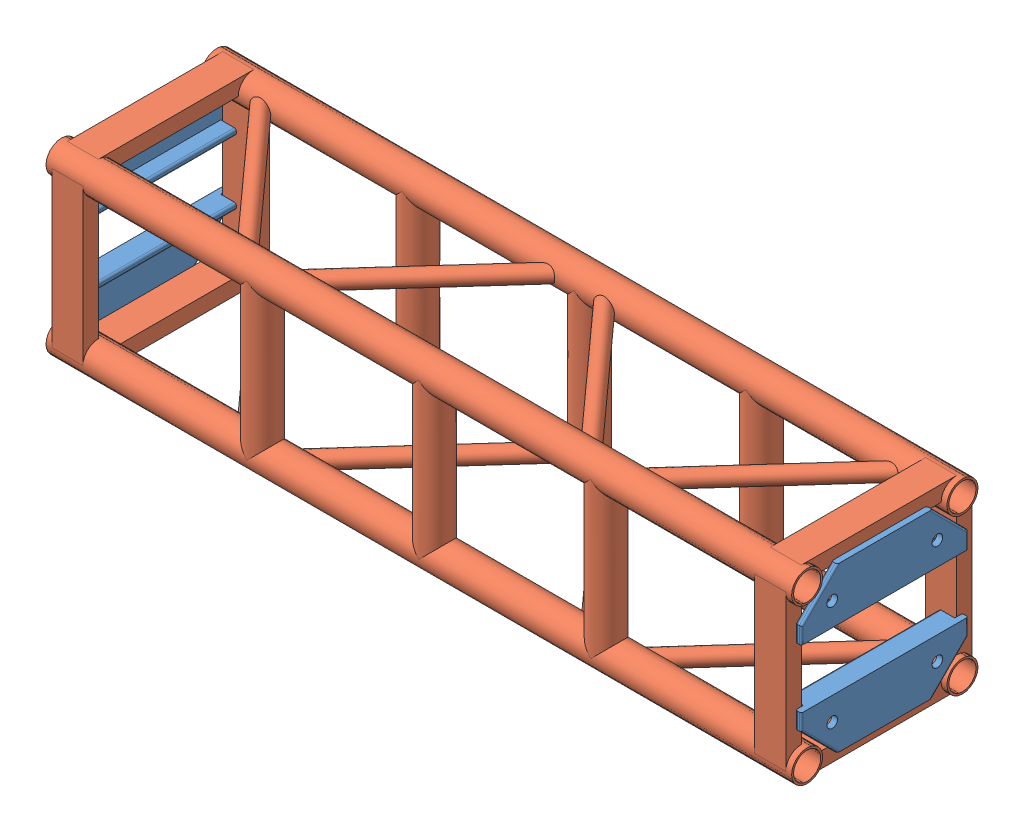
SolidWorks assembly FE-01002, configuration Default. Lengths in mm.
Overall size (1219.2 304.8 304.81).
5 component instances, 2 part files, 0 mates.
Components (placement in the parent):
- Connection Plate _ TS Standard-1: Connection Plate _ TS Standard [Default] at (-592.1375 -90.7415 0) x (0 0 -1) z (1 0 0) size (273.05 85.72 34.92)
- Connection Plate _ TS Standard-2: Connection Plate _ TS Standard [Default] at (-592.1375 90.7415 0) x (0 0 1) z (1 0 0) size (273.05 85.72 34.92)
- Connection Plate _ TS Standard-3: Connection Plate _ TS Standard [Default] at (592.1375 90.7415 0) x (0 0 -1) z (-1 0 0) size (273.05 85.72 34.92)
- Connection Plate _ TS Standard-4: Connection Plate _ TS Standard [Default] at (592.1375 -90.7415 0) x (0 0 1) z (-1 0 0) size (273.05 85.72 34.92)
- FE-01002-01-1: FE-01002-01 [Default] at origin size (1219.2 304.8 304.81)
